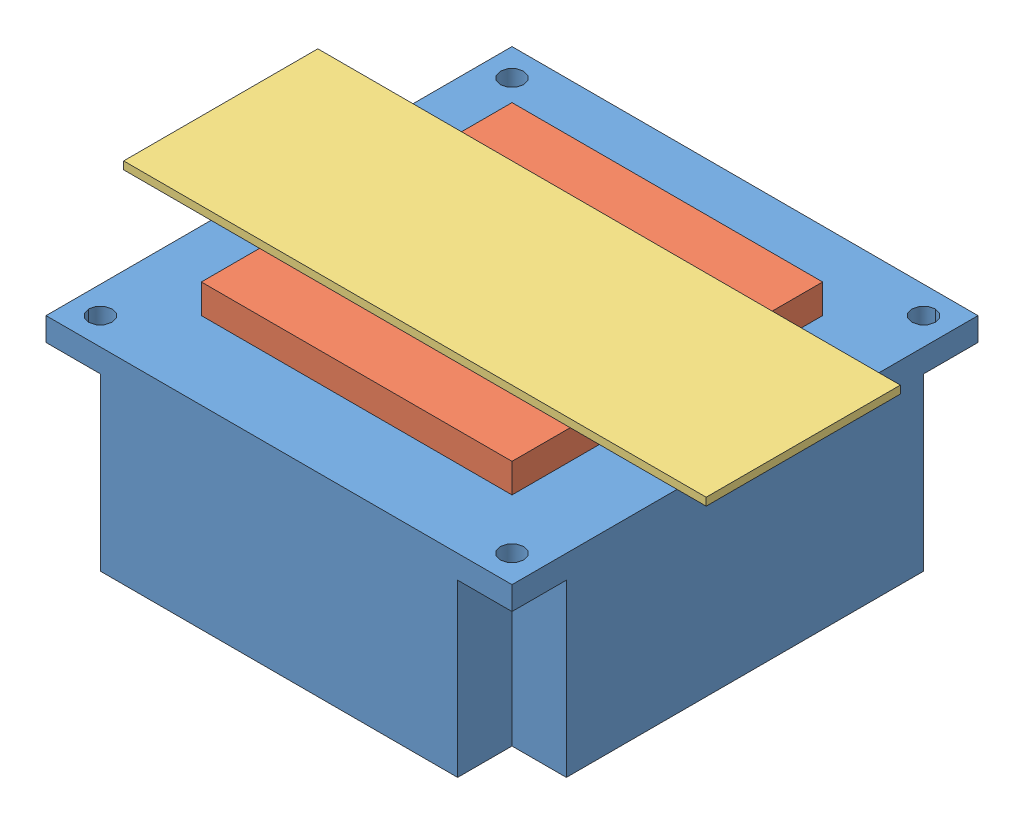
SolidWorks assembly Slide_Peltier_Heatsink, configuration Default. Lengths in mm.
Overall size (75 29.75 60).
4 component instances, 3 part files, 3 mates.
Components (placement in the parent):
- HeatSink_Peltier-3: HeatSink_Peltier [Default] at (-10.0188 -2.8403 8.4903) size (60 28.75 60)
  - HeatSink-1: HeatSink [Default] at (-6.3433 -22.0506 -73.1894) x (1 0 0) z (0 0 -1) size (60 25 60)
  - Peltier_40mm-1: Peltier_40mm [Default] at (3.6567 -18.3006 -63.1894) x (1 0 0) z (0 -1 0) size (40 40 3.75)
- Microscope_Slide-1: Microscope_Slide [Default] at (-23.8621 -21.1409 -22.1991) size (75 1 25)
Mates (geometry in assembly coordinates):
- Coincident1: coincident anti-aligned: plane of HeatSink_Peltier-3/Peltier_40mm-1 through (-6.3621 -21.1409 -54.6991) normal (0 1 0); plane of Microscope_Slide-1 through (-23.8621 -21.1409 -22.1991) normal (0 -1 0)
- Parallel1: parallel aligned: plane of HeatSink_Peltier-3/Peltier_40mm-1 through (-6.3621 -24.8909 -14.6991) normal (0 0 1); plane of Microscope_Slide-1 through (-23.8621 -20.1409 -22.1991) normal (0 0 1)
- Concentric1: concentric aligned: circle of HeatSink_Peltier-3/Peltier_40mm-1; circle of Microscope_Slide-1
